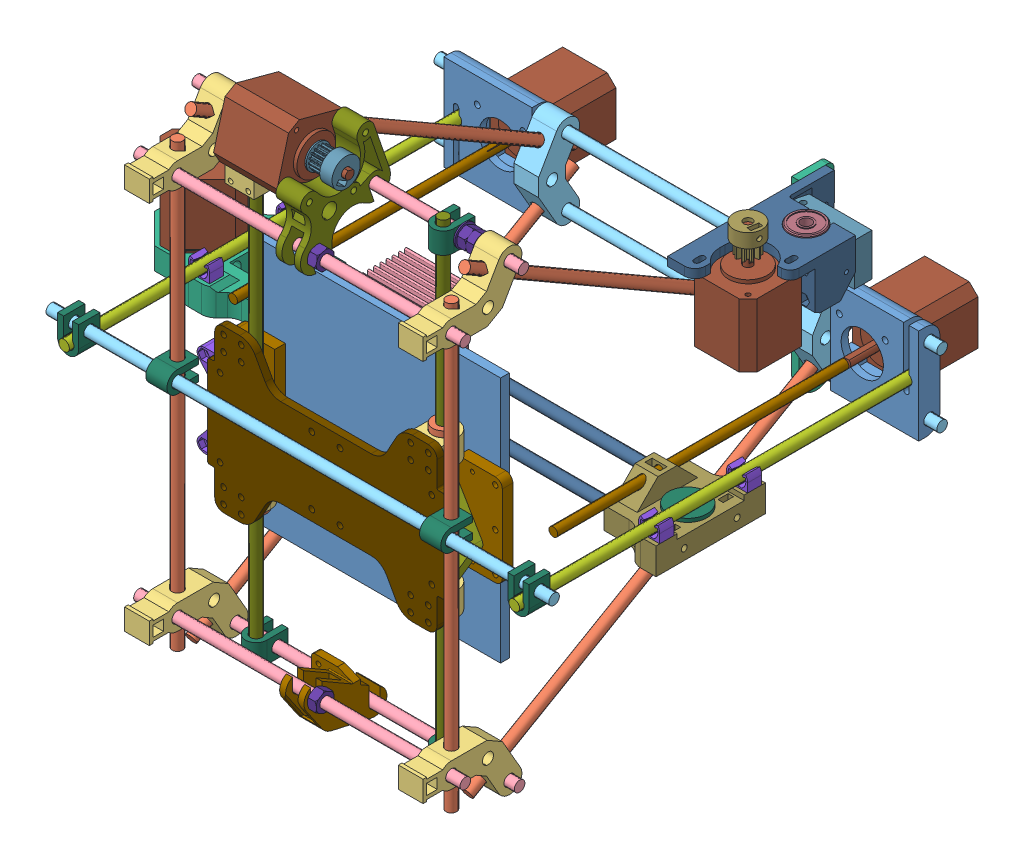
SolidWorks assembly eMAKER huxley, configuration Default. Lengths in mm.
Overall size (320.35 301.66 278.93).
103 component instances, 46 part files, 161 mates.
Components (placement in the parent):
- z-motor-bracket-3: z-motor-bracket [Default] at (-30.685 -17.6925 28.2121) size (50 54.1 12)
- M6x250-1: M6x250 [Default] at (26.315 14.5091 24.1308) x (-0.863161 -0.437281 0.252464) z (0 0.5 0.866025) size (6 6 250)
- frame-vertex-foot-2: frame-vertex-foot [Default] at (19.315 117.86 255.1395) x (0 -1 0) z (1 0 0) size (33.05 56 14)
- frame-vertex-foot-3: frame-vertex-foot [Default] at (33.315 -99.14 255.1395) x (0 1 0) z (-1 0 0) size (33.05 56 14)
- M6x250-3: M6x250 [Default] at (26.315 -120.647 240.3909) x (-0.654172 -0.655015 -0.378173) z (0 0.5 -0.866025) size (6 6 250)
- M6x250-4: M6x250 [Default] at (181.515 5.1965 22.4237) x (-0.767457 -0.555209 -0.32055) z (0 -0.5 0.866025) size (6 6 250)
- M6x250-5: M6x250 [Default] at (181.515 14.5091 24.1308) x (-0.550207 0.723156 -0.417514) z (0 0.5 0.866025) size (6 6 250)
- M6x250-6: M6x250 [Default] at (181.515 127.3875 248.1395) x (0.965547 0 0.260228) z (0 -1 0) size (6 6 250)
- frame-vertex-foot-5: frame-vertex-foot [Default] at (174.515 117.86 255.1395) x (0 -1 0) z (1 0 0) size (33.05 56 14)
- frame-vertex-foot-6: frame-vertex-foot [Default] at (188.515 -99.14 255.1395) x (0 1 0) z (-1 0 0) size (33.05 56 14)
- z-motor-bracket-4: z-motor-bracket [Default] at (238.515 36.4125 28.2121) x (-1 0 0) z (0 0 1) size (50 54.1 12)
- M6x185-19: M6x185 [Default] at (11.4609 136.9125 222.1396) x (0 -0.811297 -0.584634) z (1 0 0) size (6 6 185)
- M6x185-18: M6x185 [Default] at (196.4609 -99.14 255.1395) x (0 -0.62662 0.779325) z (-1 0 0) size (6 6 185)
- M6x285-9: M6x285 [Default] at (245.775 -9.6925 34.2121) x (0 0.518528 0.85506) z (-1 0 0) size (6 6 285)
- M6x285-10: M6x285 [Default] at (245.775 28.4125 34.2121) x (0 0.519725 0.854334) z (-1 0 0) size (6 6 285)
- x-motor-bracket-1: x-motor-bracket [Default] at (-71.685 -10.79 180.1197) x (1 0 0) z (0 1 0) size (79.5 62 24.15)
- z-smooth-rod-11: z-smooth-rod [Default] at (-23.685 9.36 27.4555) x (0.934619 -0.35565 0) z (0 0 1) size (6 6 235)
- 6mm prusa bushing-1: 6mm prusa bushing [Default] at (-23.685 9.36 186.0197) x (1 0 0) z (0 0 -1) size (12 13.42 8)
- M5x165-1: M5x165 [Default] at (1.315 9.36 26.6663) size (5 5 165)
- x-smooth-rod-12: x-smooth-rod [Default] at (226.0938 -4.79 172.1197) x (0 0.339962 0.940439) z (-1 0 0) size (6 6 265)
- x-smooth-rod-13: x-smooth-rod [Default] at (226.0938 -4.79 142.1197) x (0 0.525009 0.851096) z (-1 0 0) size (6 6 265)
- SY35ST26-1: SY35ST26 [Default] at (1.315 9.36 -7.7879) size (35.2 35.2 57)
- SY35ST26-2: SY35ST26 [Default] at (-49.685 37.61 157.1197) x (0.707107 0 -0.707107) z (0 -1 0) size (35.2 35.2 57)
- x-idler-bracket-1: x-idler-bracket [Default] at (259.515 -10.79 134.1197) x (-1 0 0) z (0 1 0) size (37.5 62 24.15)
- 6mm prusa bushing-2: 6mm prusa bushing [Default] at (-23.685 9.36 136.2197) x (1 0 0) z (0 0 -1) size (12 13.42 8)
- 6mm prusa bushing-3: 6mm prusa bushing [Default] at (231.515 9.36 136.2197) x (1 0 0) z (0 0 -1) size (12 13.42 8)
- 6mm prusa bushing-4: 6mm prusa bushing [Default] at (231.515 9.36 186.0197) x (1 0 0) z (0 0 -1) size (12 13.42 8)
- z-smooth-rod-14: z-smooth-rod [Default] at (231.515 9.36 27.4555) x (0.911514 -0.411268 0) z (0 0 1) size (6 6 235)
- M5x165-2: M5x165 [Default] at (206.515 9.36 50.3085) x (0.668515 -0.743699 0) z (0 0 1) size (5 5 165)
- SY35ST26-3: SY35ST26 [Default] at (206.515 9.36 -7.7879) size (35.2 35.2 57)
- x-carriage-1: x-carriage [Default] at (38.366 -13.79 170.1197) x (1 0 0) z (0 1 0) size (40 48 15.15)
- T2_5x16-drive-pulley 00-3: T2_5x16-drive-pulley 00 [Pulley-16-T2,5-16-2-Mekanex] at (-49.685 -1.7881 157.1197) x (0 -1 0) z (-0.972248 0 -0.233951) size (16.4 16 16)
- idler-cover-1: idler-cover [Default] at (224.515 3.61 157.1197) x (0.998064 0 -0.062193) z (0 -1 0) size (21.8 21.8 6.5)
- M6x185-20: M6x185 [Default] at (11.4609 117.86 255.1395) x (0 -0.811297 -0.584634) z (1 0 0) size (6 6 185)
- y-motor-bracket-1: y-motor-bracket [Default] at (98.0023 154.9125 243.1396) x (0 -1 0) z (1 0 0) size (60.24 51 14)
- SY35ST26-4: SY35ST26 [Default] at (62.0023 154.9125 243.1396) x (0 -0.258819 -0.965926) z (1 0 0) size (35.2 35.2 57)
- T2_5x16-drive-pulley 00-4: T2_5x16-drive-pulley 00 [Pulley-16-T2,5-16-2-Mekanex] at (100.9004 154.9125 243.1396) x (1 0 0) z (0 -0.512087 -0.858933) size (16.4 16 16)
- NORDEX-DJS-M4-6-1: NORDEX-DJS-M4-6 [DJS-M4-6] at (117.0023 117.86 255.1395) x (0 0.278292 0.960497) z (-1 0 0) size (10 11.1 5)
- nozzle-mounting-1: nozzle-mounting [Default] at (58.366 1.36 161.0197) x (1 0 0) z (0 1 0) size (40 28.8 11)
- extruder-nozzle-assy 00-1: extruder-nozzle-assy 00 [Default] at (63.5779 17.5931 168.6891) x (-1 0 0) z (0 0 1) size (38 22.2 54)
  - heater-block-1: heater-block [Default] at (-5.288 -2.2669 4.3305) size (15 15 8)
  - heatsink-block-1: heatsink-block [Default] at (24.212 12.2331 0.3305) x (-1 0 0) z (0 -1 0) size (38 8 8)
  - barrel-1: barrel [Default] at (5.212 8.2331 8.3305) x (0.956054 0.29319 0) z (0 0 -1) size (5 5 13)
  - heatsink-1: heatsink [Default] at (24.212 4.2331 -18.6695) x (0 0 -1) z (-1 0 0) size (38 10.2 38)
  - heat-shield-1: heat-shield [Default] at (5.212 12.7331 12.3305) x (1 0 0) z (0 1 0) size (38 20 3)
  - heat-spacer-1: heat-spacer [Default] at (5.212 4.2331 -7.6695) x (-1 0 0) z (0 0 -1) size (38 8 3)
  - nozzle-1: nozzle [Default] at (5.212 8.2331 16.3305) x (-0.923728 -0.383049 0) z (0 0 -1) size (5 5 8)
  - nozzle-shield-1: nozzle-shield [Default] at (5.212 8.2331 12.3305) size (16 16 3.5)
- M6x250-16: M6x250 [Default] at (26.315 129.077 248.1395) x (0.996264 0 0.086361) z (0 -1 0) size (6 6 250)
- M6x185-17: M6x185 [Default] at (194.233 -118.1925 222.1396) x (0 0.636552 -0.771234) z (-1 0 0) size (6 6 185)
- y-idler-bracket-1: y-idler-bracket [Default] at (98.0023 -332.3009 222.1722) x (1 0 0) z (0 0.000042 1) size (23.8 32.28 47)
- NORDEX-DJS-M4-6-2: NORDEX-DJS-M4-6 [DJS-M4-6] at (117.0023 -99.14 255.1395) x (0 -0.039629 0.999214) z (-1 0 0) size (10 11.1 5)
- extruder-drive 00-1: extruder-drive 00 [Default] at (193.707 73.5909 70.6403) x (0 0 -1) z (0 -1 0) size (89.5 61.93 59)
  - M6-Block-1: M6-Block [Default] at (7.0532 4.408 -6.7166) size (89.5 43 28)
  - SY35ST26-1: SY35ST26 [Default] at (-25.9468 4.408 34.2834) x (-1 0 0) z (0 0 -1) size (35.2 35.2 57)
  - 6mm hob-1: 6mm hob [Default] at (7.0532 4.408 -0.7269) x (0.604093 -0.796913 0) z (0 0 1) size (8 8 15)
  - Spur Gear MOD 1 60 tooth-1: Spur Gear MOD 1 60 tooth [Spur-Gear-10060-M08-Mekanex] at (7.0532 4.408 -8.7166) size (61.93 61.93 16) (hidden)
  - Spur-Gear-10010-M08-Mekanex 5mm bore-1: Spur-Gear-10010-M08-Mekanex 5mm bore [Spur-Gear-10010-M08-Mekanex] at (-25.9468 4.408 -8.7166) x (0.986376 0.164509 0) z (0 0 1) size (16 16 16)
  - 624-bearing-1: 624-bearing [Default] at (7.0532 4.408 20.7834) x (-0.515821 0.856696 0) z (0 0 1) size (19 19 6)
  - 624-bearing-2: 624-bearing [Default] at (7.0532 4.408 -3.2166) x (-0.515821 0.856696 0) z (0 0 1) size (19 19 6)
  - idler-bracket-1: idler-bracket [Default] at (20.3032 4.408 -3.1666) x (0 1 0) z (0 0 1) size (37 10 24)
  - 624-bearing-3: 624-bearing [Default] at (20.3032 4.408 10.3334) x (-0.515821 0.856696 0) z (0 0 1) size (19 19 6)
- y-bar-clamp-1: y-bar-clamp [Default] at (50.915 142.9125 228.1396) x (0 0 -1) z (0 -1 0) size (18 12 12)
- y-bar-clamp-2: y-bar-clamp [Default] at (156.915 142.9125 228.1396) x (0 0 -1) z (0 -1 0) size (18 12 12)
- y-bar-clamp-3: y-bar-clamp [Default] at (50.915 -112.1925 228.1396) x (0 0 -1) z (0 -1 0) size (18 12 12)
- y-bar-clamp-4: y-bar-clamp [Default] at (156.915 -112.1925 228.1396) x (0 0 -1) z (0 -1 0) size (18 12 12)
- y-bar-clamp-5: y-bar-clamp [Default] at (231.515 9.36 248.1395) x (0 1 0) z (0 0 1) size (18 12 12)
- y-bar-clamp-6: y-bar-clamp [Default] at (187.515 15.36 254.1395) x (0 0 -1) z (-1 0 0) size (18 12 12)
- y-bar-clamp-7: y-bar-clamp [Default] at (32.315 15.36 254.1395) x (0 0 -1) z (-1 0 0) size (18 12 12)
- y-bar-clamp-8: y-bar-clamp [Default] at (-23.685 9.36 248.1395) x (0 1 0) z (0 0 1) size (18 12 12)
- y-smooth-rod-18: y-smooth-rod [Default] at (156.915 146.1076 228.1396) x (-0.289261 0 0.95725) z (0 -1 0) size (6 6 270)
- y-smooth-rod-19: y-smooth-rod [Default] at (50.915 146.1076 228.1396) x (-0.633039 0 -0.77412) z (0 -1 0) size (6 6 270)
- M6-washer-thin-1: M6-washer-thin [Default] at (34.115 136.9125 222.1396) x (0 0 1) z (-1 0 0) size (12.3 12.3 0.8)
- M6-washer-thin-2: M6-washer-thin [Default] at (44.915 136.9125 222.1396) x (0 0 1) z (-1 0 0) size (12.3 12.3 0.8)
- M6-washer-thin-3: M6-washer-thin [Default] at (163.715 136.9125 222.1396) x (0 0 1) z (-1 0 0) size (12.3 12.3 0.8)
- M6-washer-thin-4: M6-washer-thin [Default] at (174.515 136.9125 222.1396) x (0 0 1) z (-1 0 0) size (12.3 12.3 0.8)
- NORDEX-DJS-M4-6-3: NORDEX-DJS-M4-6 [DJS-M4-6] at (39.115 136.9125 222.1396) x (0 -0.039629 0.999214) z (-1 0 0) size (10 11.1 5)
- NORDEX-DJS-M4-6-4: NORDEX-DJS-M4-6 [DJS-M4-6] at (44.115 136.9125 222.1396) x (0 -0.039629 0.999214) z (-1 0 0) size (10 11.1 5)
- NORDEX-DJS-M4-6-5: NORDEX-DJS-M4-6 [DJS-M4-6] at (173.715 136.9125 222.1396) x (0 -0.039629 0.999214) z (-1 0 0) size (10 11.1 5)
- NORDEX-DJS-M4-6-6: NORDEX-DJS-M4-6 [DJS-M4-6] at (168.715 136.9125 222.1396) x (0 -0.039629 0.999214) z (-1 0 0) size (10 11.1 5)
- frog-1: frog [Default] at (166.8514 -49.8233 237.6396) x (0 1 0) z (0 0 1) size (91.6 134 4)
- NORDEX-DJS-M4-6-7: NORDEX-DJS-M4-6 [DJS-M4-6] at (98.2023 -118.1925 222.1396) x (0 -0.039629 0.999214) z (-1 0 0) size (10 11.1 5)
- NORDEX-DJS-M4-6-8: NORDEX-DJS-M4-6 [DJS-M4-6] at (98.0023 136.9125 222.1396) x (0 -0.708811 0.705398) z (-1 0 0) size (10 11.1 5)
- bed-plate-1: bed-plate [Default] at (173.915 67.284 207.6396) x (-1 0 0) z (0 0 1) size (140 140 5)
- LM6UU-1: LM6UU [Default] at (48.866 -4.79 142.1197) x (0 0.332887 -0.942967) z (1 0 0) size (12 12 19)
- LM6UU-2: LM6UU [Default] at (48.866 -4.79 172.1197) x (0 0.332887 -0.942967) z (1 0 0) size (12 12 19)
- bearing-holder-1: bearing-holder [Default] at (156.915 28.0345 228.1396) x (0 0 -1) z (0 1 0) size (17.75 16.5 13.5)
- LM6UU-3: LM6UU [Default] at (156.915 25.8345 228.1396) x (-0.937496 0 -0.347997) z (0 1 0) size (12 12 19)
- bearing-holder-2: bearing-holder [Default] at (50.915 109.8872 228.1396) x (0 0 -1) z (0 1 0) size (17.75 16.5 13.5)
- LM6UU-4: LM6UU [Default] at (50.915 107.6872 228.1396) x (-0.12842 0 -0.99172) z (0 1 0) size (12 12 19)
- bearing-holder-3: bearing-holder [Default] at (156.915 -33.2655 228.1396) x (0 0 -1) z (0 -1 0) size (17.75 16.5 13.5)
- LM6UU-5: LM6UU [Default] at (156.915 -48.9655 228.1396) x (-0.937496 0 -0.347997) z (0 1 0) size (12 12 19)
- y-belt-clip-1: y-belt-clip [Default] at (100.315 2.6554 240.1396) x (0 -1 0) z (1 0 0) size (13.5 5 7)
- frame-vertex-1: frame-vertex [Default] at (188.515 -9.6925 34.2121) x (0 -0.5 0.866025) z (-1 0 0) size (33.05 47 14)
- frame-vertex-2: frame-vertex [Default] at (33.315 -9.6925 34.2121) x (0 -0.5 0.866025) z (-1 0 0) size (33.05 47 14)
- extruder-drive-holder-1: extruder-drive-holder [Default] at (174.515 1.0025 31.2121) x (0 1 0) z (-1 0 0) size (108 20 4)
- bearing-holder-4: bearing-holder [Default] at (50.915 -33.2655 228.1396) x (0 0 -1) z (0 -1 0) size (17.75 16.5 13.5)
- LM6UU-6: LM6UU [Default] at (50.915 -31.0655 228.1396) x (-0.649924 0 0.759999) z (0 -1 0) size (12 12 19)
- spring-anchor-double-1: spring-anchor-double [Default] at (159.915 23.3853 229.6396) x (0 -1 0) z (0 0 1) size (52 21 8)
- spring-anchor-single-1: spring-anchor-single [Default] at (47.915 -28.6147 229.6396) x (0 1 0) z (0 0 1) size (52 21 8)
- M6x285-11: M6x285 [Default] at (245.775 15.36 254.1395) x (0 0.518528 0.85506) z (-1 0 0) size (6 6 285)
- bed-mounting-plate-1: bed-mounting-plate [Default] at (155.915 23.284 212.6396) x (0 -1 0) z (0 0 1) size (52 25 6)
- bed-mounting-plate-2: bed-mounting-plate [Default] at (51.915 -28.716 212.6396) x (0 1 0) z (0 0 1) size (52 25 6)
Mates (geometry in assembly coordinates):
- Coincident8: coincident aligned: plane of M6x250-1 through (26.315 14.5091 24.1308) normal (0 -0.5 -0.866025); plane of M6x250-5 through (181.515 14.5091 24.1308) normal (0 -0.5 -0.866025)
- Coincident12: coincident aligned: plane of M6x185-19 through (11.4609 136.9125 222.1396) normal (-1 0 0); plane of M6x185-18 through (11.4609 -99.14 255.1395) normal (-1 0 0)
- Coincident13: coincident aligned: plane of M6x285-9 through (245.775 -9.6925 34.2121) normal (1 0 0); plane of M6x285-10 through (245.775 28.4125 34.2121) normal (1 0 0)
- Concentric22: concentric aligned: cylinder of z-motor-bracket-3 through (-23.685 9.36 40.2121) axis (0 0 -1) radius 3.15; cylinder of z-smooth-rod-11 through (-23.685 9.36 262.4555) axis (0 0 -1) radius 3
- Concentric25: concentric aligned: cylinder of z-motor-bracket-3 through (1.315 9.36 40.2121) axis (0 0 -1) radius 12; cylinder of M5x165-1 through (1.315 9.36 191.6663) axis (0 0 -1) radius 2.5
- Concentric26: concentric aligned: cylinder of x-motor-bracket-1 through (-37.185 -4.79 172.1197) axis (1 0 0) radius 3.15; cylinder of x-smooth-rod-12 through (-38.9062 -4.79 172.1197) axis (1 0 0) radius 3
- Concentric27: concentric aligned: cylinder of x-motor-bracket-1 through (-37.185 -4.79 142.1197) axis (1 0 0) radius 3.15; cylinder of x-smooth-rod-13 through (-38.9062 -4.79 142.1197) axis (1 0 0) radius 3
- Coincident16: coincident aligned: plane of x-smooth-rod-12 through (226.0938 -4.79 172.1197) normal (1 0 0); plane of x-smooth-rod-13 through (226.0938 -4.79 142.1197) normal (1 0 0)
- Concentric28: concentric anti-aligned: cylinder of z-motor-bracket-3 through (-11.685 -3.64 40.2121) axis (0 0 -1) radius 1.7; cylinder of SY35ST26-1 through (-11.685 -3.64 28.2121) axis (0 0 1) radius 1.25
- Concentric29: concentric anti-aligned: cylinder of z-motor-bracket-3 through (14.315 22.36 40.2121) axis (0 0 -1) radius 1.7; cylinder of SY35ST26-1 through (14.315 22.36 28.2121) axis (0 0 1) radius 1.25
- Coincident17: coincident anti-aligned: plane of z-motor-bracket-3 through (-30.685 36.4125 28.2121) normal (0 0 -1); plane of SY35ST26-1 through (-16.285 26.96 28.2121) normal (0 0 1)
- Concentric30: concentric anti-aligned: cylinder of x-motor-bracket-1 through (-49.685 -10.79 175.5044) axis (0 1 0) radius 1.75; cylinder of SY35ST26-2 through (-49.685 1.61 175.5044) axis (0 -1 0) radius 1.25
- Concentric31: concentric anti-aligned: cylinder of x-motor-bracket-1 through (-49.685 -10.79 138.7349) axis (0 1 0) radius 1.75; cylinder of SY35ST26-2 through (-49.685 1.61 138.7349) axis (0 -1 0) radius 1.25
- Coincident18: coincident anti-aligned: plane of x-motor-bracket-1 through (-30.685 1.61 134.1197) normal (0 1 0); plane of SY35ST26-2 through (-49.685 1.61 182.0098) normal (0 -1 0)
- Concentric34: concentric anti-aligned: cylinder of x-smooth-rod-13 through (-38.9062 -4.79 142.1197) axis (1 0 0) radius 3; cylinder of x-idler-bracket-1 through (246.4245 -4.79 142.1197) axis (-1 0 0) radius 3.15
- Concentric35: concentric anti-aligned: cylinder of x-smooth-rod-12 through (-38.9062 -4.79 172.1197) axis (1 0 0) radius 3; cylinder of x-idler-bracket-1 through (246.4245 -4.79 172.1197) axis (-1 0 0) radius 3.15
- Concentric39: concentric aligned: cylinder of z-motor-bracket-4 through (231.515 9.36 40.2121) axis (0 0 -1) radius 3.15; cylinder of z-smooth-rod-14 through (231.515 9.36 262.4555) axis (0 0 -1) radius 3
- Coincident23: coincident aligned: plane of z-smooth-rod-11 through (-23.685 9.36 27.4555) normal (0 0 -1); plane of z-smooth-rod-14 through (231.515 9.36 27.4555) normal (0 0 -1)
- Concentric42: concentric anti-aligned: cylinder of z-motor-bracket-4 through (193.515 -3.64 40.2121) axis (0 0 -1) radius 1.7; cylinder of SY35ST26-3 through (193.515 -3.64 28.2121) axis (0 0 1) radius 1.25
- Concentric43: concentric anti-aligned: cylinder of z-motor-bracket-4 through (219.515 22.36 40.2121) axis (0 0 -1) radius 1.7; cylinder of SY35ST26-3 through (219.515 22.36 28.2121) axis (0 0 1) radius 1.25
- Coincident26: coincident anti-aligned: plane of z-motor-bracket-4 through (238.515 -17.6925 28.2121) normal (0 0 -1); plane of SY35ST26-3 through (188.915 26.96 28.2121) normal (0 0 1)
- Concentric51: concentric aligned: cylinder of SY35ST26-2 through (-49.685 -19.39 157.1197) axis (0 1 0) radius 2.5; cylinder of T2_5x16-drive-pulley 00-3 through (-49.685 -1.7881 157.1197) axis (0 1 0) radius 2.65
- Distance6: distance = 1 mm anti-aligned: plane of T2_5x16-drive-pulley 00-3 through (-50.2798 -1.39 159.5914) normal (0 1 0); plane of SY35ST26-2 through (-49.685 -0.39 157.1197) normal (0 -1 0)
- Concentric53: concentric aligned: cylinder of x-idler-bracket-1 through (224.515 -10.79 157.1197) axis (0 1 0) radius 1.65; cylinder of idler-cover-1 through (224.515 -2.89 157.1197) axis (0 1 0) radius 1.65
- Coincident36: coincident anti-aligned: plane of x-idler-bracket-1 through (200.015 1.61 180.1197) normal (0 1 0); plane of idler-cover-1 through (224.515 1.61 157.1197) normal (0 -1 0)
- Coincident38: coincident aligned: plane of M6x185-19 through (196.4609 136.9125 222.1396) normal (1 0 0); plane of M6x185-20 through (196.4609 117.86 255.1395) normal (1 0 0)
- Concentric65: concentric aligned: cylinder of M6x185-19 through (196.4609 136.9125 222.1396) axis (-1 0 0) radius 3; cylinder of y-motor-bracket-1 through (112.0023 136.9125 222.1396) axis (-1 0 0) radius 3.15
- Concentric69: concentric aligned: cylinder of y-motor-bracket-1 through (112.0023 154.9125 243.1396) axis (-1 0 0) radius 13; cylinder of SY35ST26-4 through (100.0023 154.9125 243.1396) axis (-1 0 0) radius 11
- Concentric70: concentric anti-aligned: cylinder of y-motor-bracket-1 through (112.0023 138.9908 233.9472) axis (-1 0 0) radius 1.65; cylinder of SY35ST26-4 through (98.0023 138.9908 233.9472) axis (1 0 0) radius 1.25
- Coincident39: coincident anti-aligned: plane of y-motor-bracket-1 through (98.0023 132.7028 269.9952) normal (-1 0 0); plane of SY35ST26-4 through (98.0023 176.468 255.5847) normal (1 0 0)
- Concentric71: concentric aligned: cylinder of SY35ST26-4 through (119.0023 154.9125 243.1396) axis (-1 0 0) radius 2.5; cylinder of T2_5x16-drive-pulley 00-4 through (100.9004 154.9125 243.1396) axis (-1 0 0) radius 2.65
- Concentric72: concentric anti-aligned: cylinder of M6x185-20 through (196.4609 117.86 255.1395) axis (-1 0 0) radius 3; cylinder of NORDEX-DJS-M4-6-1 through (112.0023 117.86 255.1395) axis (1 0 0) radius 3
- Coincident41: coincident anti-aligned: plane of y-motor-bracket-1 through (112.0023 132.7028 269.9952) normal (1 0 0); plane of NORDEX-DJS-M4-6-1 through (112.0023 119.1339 249.5648) normal (-1 0 0)
- Concentric77: concentric aligned: cylinder of nozzle-mounting-1 through (70.866 1.36 158.1197) axis (0 1 0) radius 1.65; cylinder of x-carriage-1 through (70.866 -13.79 158.1197) axis (0 1 0) radius 1.35
- Concentric78: concentric aligned: cylinder of x-carriage-1 through (45.866 -13.79 158.1197) axis (0 1 0) radius 1.35; cylinder of nozzle-mounting-1 through (45.866 1.36 158.1197) axis (0 1 0) radius 1.65
- Coincident43: coincident anti-aligned: plane of x-carriage-1 through (38.366 1.36 161.1197) normal (0 1 0); plane of nozzle-mounting-1 through (38.366 1.36 132.2197) normal (0 -1 0)
- Distance10: distance = 3 mm anti-aligned: plane of extruder-nozzle-assy 00-1/heatsink-block-1 through (39.366 13.36 161.0197) normal (0 0 -1); plane of nozzle-mounting-1 through (38.366 4.36 158.0197) normal (0 0 1)
- Concentric81: concentric aligned: cylinder of nozzle-mounting-1 through (65.866 9.36 161.0197) axis (0 0 -1) radius 1.65; cylinder of extruder-nozzle-assy 00-1/heatsink-block-1 through (65.866 9.36 161.0197) axis (0 0 -1) radius 1.25
- Concentric82: concentric aligned: cylinder of nozzle-mounting-1 through (50.866 9.36 161.0197) axis (0 0 -1) radius 1.65; cylinder of extruder-nozzle-assy 00-1/heatsink-block-1 through (50.866 9.36 161.0197) axis (0 0 -1) radius 1.25
- Concentric86: concentric anti-aligned: cylinder of M6x250-1 through (26.315 139.5091 240.6371) axis (0 -0.5 -0.866025) radius 3; cylinder of frame-vertex-foot-2 through (26.315 121.306 209.1085) axis (0 0.5 0.866025) radius 3.2
- Concentric88: concentric anti-aligned: cylinder of M6x250-4 through (181.515 -119.8035 238.93) axis (0 0.5 -0.866025) radius 3; cylinder of frame-vertex-foot-6 through (181.515 -102.5861 209.1085) axis (0 -0.5 0.866025) radius 3.2
- Concentric89: concentric aligned: cylinder of frame-vertex-foot-5 through (174.515 136.9125 222.1396) axis (-1 0 0) radius 3.2; cylinder of M6x185-19 through (196.4609 136.9125 222.1396) axis (-1 0 0) radius 3
- Concentric90: concentric aligned: cylinder of frame-vertex-foot-5 through (174.515 117.86 255.1395) axis (-1 0 0) radius 3.2; cylinder of M6x185-20 through (196.4609 117.86 255.1395) axis (-1 0 0) radius 3
- Concentric91: concentric anti-aligned: cylinder of M6x250-5 through (181.515 139.5091 240.6371) axis (0 -0.5 -0.866025) radius 3; cylinder of frame-vertex-foot-5 through (181.515 121.306 209.1085) axis (0 0.5 0.866025) radius 3.2
- Concentric92: concentric aligned: cylinder of frame-vertex-foot-2 through (19.315 136.9125 222.1396) axis (-1 0 0) radius 3.2; cylinder of M6x185-19 through (196.4609 136.9125 222.1396) axis (-1 0 0) radius 3
- Concentric93: concentric aligned: cylinder of M6x250-6 through (181.515 -122.6125 248.1395) axis (0 1 0) radius 3; cylinder of frame-vertex-foot-5 through (181.515 110.86 248.1395) axis (0 1 0) radius 3.2
- Concentric94: concentric anti-aligned: cylinder of M6x250-6 through (181.515 -122.6125 248.1395) axis (0 1 0) radius 3; cylinder of frame-vertex-foot-6 through (181.515 -92.14 248.1395) axis (0 -1 0) radius 3.2
- Concentric95: concentric aligned: cylinder of frame-vertex-foot-2 through (26.315 110.86 248.1395) axis (0 1 0) radius 3.2; cylinder of M6x250-16 through (26.315 -120.923 248.1395) axis (0 1 0) radius 3
- Concentric96: concentric anti-aligned: cylinder of frame-vertex-foot-3 through (26.315 -92.14 248.1395) axis (0 -1 0) radius 3.2; cylinder of M6x250-16 through (26.315 -120.923 248.1395) axis (0 1 0) radius 3
- Concentric97: concentric aligned: cylinder of frame-vertex-foot-3 through (33.315 -99.14 255.1395) axis (1 0 0) radius 3.2; cylinder of M6x185-18 through (11.4609 -99.14 255.1395) axis (1 0 0) radius 3
- Concentric98: concentric aligned: cylinder of frame-vertex-foot-6 through (188.515 -99.14 255.1395) axis (1 0 0) radius 3.2; cylinder of M6x185-18 through (11.4609 -99.14 255.1395) axis (1 0 0) radius 3
- Concentric102: concentric aligned: cylinder of frame-vertex-foot-3 through (26.315 -102.5861 209.1085) axis (0 -0.5 0.866025) radius 3.2; cylinder of M6x250-3 through (26.315 4.353 23.8845) axis (0 -0.5 0.866025) radius 3
- Concentric103: concentric aligned: cylinder of frame-vertex-foot-3 through (33.315 -118.1925 222.1396) axis (1 0 0) radius 3.2; cylinder of M6x185-17 through (9.233 -118.1925 222.1396) axis (1 0 0) radius 3
- Concentric107: concentric aligned: cylinder of z-motor-bracket-4 through (206.515 9.36 40.2121) axis (0 0 -1) radius 12; cylinder of M5x165-2 through (206.515 9.36 215.3085) axis (0 0 -1) radius 2.5
- Concentric108: concentric anti-aligned: cylinder of z-smooth-rod-11 through (-23.685 9.36 262.4555) axis (0 0 -1) radius 3; cylinder of 6mm prusa bushing-2 through (-23.685 9.36 128.2197) axis (0 0 1) radius 5
- Concentric109: concentric anti-aligned: cylinder of 6mm prusa bushing-3 through (231.515 9.36 128.2197) axis (0 0 1) radius 5; cylinder of z-smooth-rod-14 through (231.515 9.36 262.4555) axis (0 0 -1) radius 3
- Concentric112: concentric anti-aligned: cylinder of x-idler-bracket-1 through (206.515 9.36 126.1197) axis (0 0 1) radius 2.7; cylinder of M5x165-2 through (206.515 9.36 215.3085) axis (0 0 -1) radius 2.5
- Concentric114: concentric aligned: cylinder of M6x185-18 through (11.4609 -99.14 255.1395) axis (1 0 0) radius 3; cylinder of y-idler-bracket-1 through (98.2023 -99.14 255.1395) axis (1 0 0) radius 3.2
- Concentric115: concentric aligned: cylinder of M6x185-17 through (9.233 -118.1925 222.1396) axis (1 0 0) radius 3; cylinder of y-idler-bracket-1 through (98.2023 -118.1926 222.1395) axis (1 0 0) radius 3.2
- Coincident52: coincident aligned: plane of y-motor-bracket-1 through (112.0023 132.7028 269.9952) normal (1 0 0); plane of y-idler-bracket-1 through (112.0023 -99.14 255.1395) normal (1 0 0)
- Coincident53: coincident anti-aligned: plane of y-idler-bracket-1 through (112.0023 -99.14 255.1395) normal (1 0 0); plane of NORDEX-DJS-M4-6-2 through (112.0023 -96.1691 250.2534) normal (-1 0 0)
- Concentric116: concentric aligned: cylinder of M6x185-18 through (11.4609 -99.14 255.1395) axis (1 0 0) radius 3; cylinder of NORDEX-DJS-M4-6-2 through (112.0023 -99.14 255.1395) axis (1 0 0) radius 3
- Concentric120: concentric anti-aligned: cylinder of M6x185-19 through (196.4609 136.9125 222.1396) axis (-1 0 0) radius 3; cylinder of y-bar-clamp-1 through (44.915 136.9125 222.1396) axis (1 0 0) radius 3.15
- Concentric121: concentric anti-aligned: cylinder of M6x185-19 through (196.4609 136.9125 222.1396) axis (-1 0 0) radius 3; cylinder of y-bar-clamp-2 through (150.915 136.9125 222.1396) axis (1 0 0) radius 3.15
- Concentric122: concentric aligned: cylinder of M6x185-17 through (9.233 -118.1925 222.1396) axis (1 0 0) radius 3; cylinder of y-bar-clamp-3 through (44.915 -118.1925 222.1396) axis (1 0 0) radius 3.15
- Concentric123: concentric aligned: cylinder of M6x185-17 through (9.233 -118.1925 222.1396) axis (1 0 0) radius 3; cylinder of y-bar-clamp-4 through (150.915 -118.1925 222.1396) axis (1 0 0) radius 3.15
- Concentric124: concentric anti-aligned: cylinder of M6x250-6 through (181.515 -122.6125 248.1395) axis (0 1 0) radius 3; cylinder of y-bar-clamp-6 through (181.515 21.36 248.1395) axis (0 -1 0) radius 3.15
- Concentric125: concentric aligned: cylinder of z-smooth-rod-14 through (231.515 9.36 262.4555) axis (0 0 -1) radius 3; cylinder of y-bar-clamp-5 through (231.515 9.36 260.1395) axis (0 0 -1) radius 3.3
- Concentric126: concentric anti-aligned: cylinder of y-bar-clamp-5 through (237.515 15.36 254.1395) axis (-1 0 0) radius 3.15; cylinder of y-bar-clamp-6 through (175.515 15.36 254.1395) axis (1 0 0) radius 3.3
- Concentric127: concentric anti-aligned: cylinder of M6x250-16 through (26.315 -120.923 248.1395) axis (0 1 0) radius 3; cylinder of y-bar-clamp-7 through (26.315 21.36 248.1395) axis (0 -1 0) radius 3.15
- Concentric128: concentric aligned: cylinder of z-smooth-rod-11 through (-23.685 9.36 262.4555) axis (0 0 -1) radius 3; cylinder of y-bar-clamp-8 through (-23.685 9.36 260.1395) axis (0 0 -1) radius 3.3
- Concentric129: concentric anti-aligned: cylinder of y-bar-clamp-7 through (20.315 15.36 254.1395) axis (1 0 0) radius 3.3; cylinder of y-bar-clamp-8 through (-17.685 15.36 254.1395) axis (-1 0 0) radius 3.15
- Concentric130: concentric aligned: cylinder of y-bar-clamp-2 through (156.915 130.9125 228.1396) axis (0 1 0) radius 3.3; cylinder of y-smooth-rod-18 through (156.915 -123.8924 228.1396) axis (0 1 0) radius 3
- Concentric131: concentric aligned: cylinder of y-bar-clamp-4 through (156.915 -124.1925 228.1396) axis (0 1 0) radius 3.3; cylinder of y-smooth-rod-18 through (156.915 -123.8924 228.1396) axis (0 1 0) radius 3
- Concentric132: concentric aligned: cylinder of y-bar-clamp-1 through (50.915 130.9125 228.1396) axis (0 1 0) radius 3.3; cylinder of y-smooth-rod-19 through (50.915 -123.8924 228.1396) axis (0 1 0) radius 3
- Concentric134: concentric aligned: cylinder of y-bar-clamp-3 through (50.915 -124.1925 228.1396) axis (0 1 0) radius 3.3; cylinder of y-smooth-rod-19 through (50.915 -123.8924 228.1396) axis (0 1 0) radius 3
- Coincident57: coincident aligned: plane of y-smooth-rod-18 through (156.915 146.1076 228.1396) normal (0 1 0); plane of y-smooth-rod-19 through (50.915 146.1076 228.1396) normal (0 1 0)
- Concentric135: concentric anti-aligned: cylinder of M6x185-19 through (196.4609 136.9125 222.1396) axis (-1 0 0) radius 3; cylinder of M6-washer-thin-1 through (33.315 136.9125 222.1396) axis (1 0 0) radius 3.25
- Concentric136: concentric anti-aligned: cylinder of M6x185-19 through (196.4609 136.9125 222.1396) axis (-1 0 0) radius 3; cylinder of NORDEX-DJS-M4-6-3 through (34.115 136.9125 222.1396) axis (1 0 0) radius 3
- Coincident59: coincident aligned: cylinder of M6x185-19 through (196.4609 136.9125 222.1396) axis (-1 0 0) radius 3; circle of NORDEX-DJS-M4-6-4
- Concentric137: concentric anti-aligned: cylinder of M6x185-19 through (196.4609 136.9125 222.1396) axis (-1 0 0) radius 3; cylinder of M6-washer-thin-2 through (44.115 136.9125 222.1396) axis (1 0 0) radius 3.25
- Coincident60: coincident anti-aligned: plane of M6-washer-thin-1 through (34.115 136.9125 222.1396) normal (1 0 0); plane of NORDEX-DJS-M4-6-3 through (34.115 139.8834 217.2535) normal (-1 0 0)
- Coincident61: coincident anti-aligned: plane of NORDEX-DJS-M4-6-3 through (39.115 139.8834 217.2535) normal (1 0 0); plane of NORDEX-DJS-M4-6-4 through (39.115 139.8834 217.2535) normal (-1 0 0)
- Coincident62: coincident anti-aligned: plane of M6-washer-thin-2 through (44.115 136.9125 222.1396) normal (-1 0 0); plane of NORDEX-DJS-M4-6-4 through (44.115 139.8834 217.2535) normal (1 0 0)
- Coincident63: coincident anti-aligned: plane of y-bar-clamp-1 through (44.915 130.9125 228.1396) normal (-1 0 0); plane of M6-washer-thin-2 through (44.915 136.9125 222.1396) normal (1 0 0)
- Concentric138: concentric anti-aligned: cylinder of M6x185-19 through (196.4609 136.9125 222.1396) axis (-1 0 0) radius 3; cylinder of M6-washer-thin-4 through (173.715 136.9125 222.1396) axis (1 0 0) radius 3.25
- Concentric139: concentric anti-aligned: cylinder of M6x185-19 through (196.4609 136.9125 222.1396) axis (-1 0 0) radius 3; cylinder of M6-washer-thin-3 through (162.915 136.9125 222.1396) axis (1 0 0) radius 3.25
- Concentric140: concentric anti-aligned: cylinder of M6x185-19 through (196.4609 136.9125 222.1396) axis (-1 0 0) radius 3; cylinder of NORDEX-DJS-M4-6-5 through (168.715 136.9125 222.1396) axis (1 0 0) radius 3
- Concentric141: concentric anti-aligned: cylinder of M6x185-19 through (196.4609 136.9125 222.1396) axis (-1 0 0) radius 3; cylinder of NORDEX-DJS-M4-6-6 through (163.715 136.9125 222.1396) axis (1 0 0) radius 3
- Coincident64: coincident anti-aligned: plane of frame-vertex-foot-5 through (174.515 117.86 255.1395) normal (-1 0 0); plane of M6-washer-thin-4 through (174.515 136.9125 222.1396) normal (1 0 0)
- Coincident65: coincident anti-aligned: plane of M6-washer-thin-4 through (173.715 136.9125 222.1396) normal (-1 0 0); plane of NORDEX-DJS-M4-6-5 through (173.715 139.8834 217.2535) normal (1 0 0)
- Coincident66: coincident anti-aligned: plane of NORDEX-DJS-M4-6-5 through (168.715 139.8834 217.2535) normal (-1 0 0); plane of NORDEX-DJS-M4-6-6 through (168.715 139.8834 217.2535) normal (1 0 0)
- Coincident67: coincident anti-aligned: plane of M6-washer-thin-3 through (163.715 136.9125 222.1396) normal (1 0 0); plane of NORDEX-DJS-M4-6-6 through (163.715 139.8834 217.2535) normal (-1 0 0)
- Coincident68: coincident anti-aligned: plane of y-bar-clamp-2 through (162.915 130.9125 228.1396) normal (1 0 0); plane of M6-washer-thin-3 through (162.915 136.9125 222.1396) normal (-1 0 0)
- Concentric146: concentric aligned: cylinder of M6x185-20 through (196.4609 117.86 255.1395) axis (-1 0 0) radius 3; cylinder of y-motor-bracket-1 through (112.0023 117.86 255.1395) axis (-1 0 0) radius 3.15
- Concentric148: concentric aligned: cylinder of M6x185-17 through (9.233 -118.1925 222.1396) axis (1 0 0) radius 3; cylinder of NORDEX-DJS-M4-6-7 through (93.2023 -118.1925 222.1396) axis (1 0 0) radius 3
- Coincident95: coincident anti-aligned: plane of y-idler-bracket-1 through (98.2023 -99.14 255.1395) normal (-1 0 0); plane of NORDEX-DJS-M4-6-7 through (98.2023 -115.2216 217.2535) normal (1 0 0)
- Concentric149: concentric anti-aligned: cylinder of M6x185-19 through (196.4609 136.9125 222.1396) axis (-1 0 0) radius 3; cylinder of NORDEX-DJS-M4-6-8 through (93.0023 136.9125 222.1396) axis (1 0 0) radius 3
- Coincident96: coincident: plane of y-motor-bracket-1 through (98.0023 132.7028 269.9952) normal (-1 0 0); line of NORDEX-DJS-M4-6-8 through (98.0023 141.1193 219.2786) axis (0 -0.705398 -0.708811)
- Concentric152: concentric aligned: cylinder of z-motor-bracket-4 through (188.515 28.4125 34.2121) axis (1 0 0) radius 3.15; cylinder of M6x285-10 through (-39.225 28.4125 34.2121) axis (1 0 0) radius 3
- Concentric153: concentric aligned: cylinder of z-motor-bracket-4 through (188.515 -9.6925 34.2121) axis (1 0 0) radius 3.15; cylinder of M6x285-9 through (-39.225 -9.6925 34.2121) axis (1 0 0) radius 3
- Concentric154: concentric anti-aligned: cylinder of z-motor-bracket-3 through (19.315 28.4125 34.2121) axis (-1 0 0) radius 3.15; cylinder of M6x285-10 through (-39.225 28.4125 34.2121) axis (1 0 0) radius 3
- Concentric155: concentric anti-aligned: cylinder of x-smooth-rod-13 through (-38.9062 -4.79 142.1197) axis (1 0 0) radius 3; cylinder of LM6UU-1 through (67.866 -4.79 142.1197) axis (-1 0 0) radius 3
- Concentric156: concentric aligned: cylinder of x-carriage-1 through (68.366 -4.79 142.1197) axis (-1 0 0) radius 6.1; cylinder of LM6UU-1 through (67.866 -4.79 142.1197) axis (-1 0 0) radius 6
- Distance26: distance = 0.5 mm anti-aligned: plane of LM6UU-1 through (67.866 -4.79 142.1197) normal (1 0 0); plane of x-carriage-1 through (68.366 -4.79 142.1197) normal (-1 0 0)
- Concentric157: concentric anti-aligned: cylinder of x-smooth-rod-12 through (-38.9062 -4.79 172.1197) axis (1 0 0) radius 3; cylinder of LM6UU-2 through (67.866 -4.79 172.1197) axis (-1 0 0) radius 3
- Concentric158: concentric aligned: cylinder of x-carriage-1 through (68.366 -4.79 172.1197) axis (-1 0 0) radius 6.1; cylinder of LM6UU-2 through (67.866 -4.79 172.1197) axis (-1 0 0) radius 6
- Distance27: distance = 0.5 mm anti-aligned: plane of x-carriage-1 through (48.366 -4.79 172.1197) normal (1 0 0); plane of LM6UU-2 through (48.866 -4.79 172.1197) normal (-1 0 0)
- Concentric159: concentric anti-aligned: cylinder of frog-1 through (161.915 39.0345 241.6396) axis (0 0 -1) radius 1.6; cylinder of bearing-holder-1 through (161.915 39.0345 237.6396) axis (0 0 1) radius 1.35
- Concentric162: concentric anti-aligned: cylinder of frog-1 through (161.915 30.5345 241.6396) axis (0 0 -1) radius 1.6; cylinder of bearing-holder-1 through (161.915 30.5345 237.6396) axis (0 0 1) radius 1.35
- Coincident100: coincident anti-aligned: plane of frog-1 through (39.915 -29.6163 237.6396) normal (0 0 -1); plane of bearing-holder-1 through (148.665 41.5345 237.6396) normal (0 0 1)
- Concentric163: concentric anti-aligned: cylinder of y-smooth-rod-18 through (156.915 -123.8924 228.1396) axis (0 1 0) radius 3; cylinder of LM6UU-3 through (156.915 44.8345 228.1396) axis (0 -1 0) radius 3
- Concentric164: concentric aligned: cylinder of bearing-holder-1 through (156.915 41.5345 228.1396) axis (0 -1 0) radius 6.2; cylinder of LM6UU-3 through (156.915 44.8345 228.1396) axis (0 -1 0) radius 6
- Coincident101: coincident anti-aligned: plane of bearing-holder-1 through (156.915 41.5345 228.1396) normal (0 1 0); circle of LM6UU-3
- Coincident58: coincident anti-aligned: plane of frame-vertex-foot-2 through (33.315 117.86 255.1395) normal (1 0 0); plane of M6-washer-thin-1 through (33.315 136.9125 222.1396) normal (-1 0 0)
- Coincident102: coincident anti-aligned: plane of frog-1 through (39.915 -29.6163 237.6396) normal (0 0 -1); plane of bearing-holder-2 through (42.665 123.3872 237.6396) normal (0 0 1)
- Concentric167: concentric anti-aligned: cylinder of y-smooth-rod-19 through (50.915 -123.8924 228.1396) axis (0 1 0) radius 3; cylinder of LM6UU-4 through (50.915 126.6872 228.1396) axis (0 -1 0) radius 3
- Coincident103: coincident anti-aligned: plane of bearing-holder-2 through (50.915 123.3872 228.1396) normal (0 1 0); plane of LM6UU-4 through (50.1765 123.3872 222.4372) normal (0 -1 0)
- Concentric169: concentric aligned: cylinder of bearing-holder-2 through (50.915 123.3872 228.1396) axis (0 -1 0) radius 6.2; cylinder of LM6UU-4 through (50.915 126.6872 228.1396) axis (0 -1 0) radius 6
- Distance29: distance = 94 mm anti-aligned: plane of y-bar-clamp-2 through (150.915 130.9125 228.1396) normal (-1 0 0); plane of y-bar-clamp-1 through (56.915 130.9125 228.1396) normal (1 0 0)
- Concentric170: concentric anti-aligned: cylinder of frog-1 through (161.915 -44.2655 241.6396) axis (0 0 -1) radius 1.6; cylinder of bearing-holder-3 through (161.915 -44.2655 237.6396) axis (0 0 1) radius 1.35
- Concentric171: concentric anti-aligned: cylinder of frog-1 through (161.915 -35.7655 241.6396) axis (0 0 -1) radius 1.6; cylinder of bearing-holder-3 through (161.915 -35.7655 237.6396) axis (0 0 1) radius 1.35
- Coincident108: coincident anti-aligned: plane of frog-1 through (39.915 -29.6163 237.6396) normal (0 0 -1); plane of bearing-holder-3 through (165.165 -46.7655 237.6396) normal (0 0 1)
- Concentric172: concentric anti-aligned: cylinder of y-smooth-rod-18 through (156.915 -123.8924 228.1396) axis (0 1 0) radius 3; cylinder of LM6UU-5 through (156.915 -29.9655 228.1396) axis (0 -1 0) radius 3
- Coincident109: coincident anti-aligned: plane of bearing-holder-3 through (156.915 -46.7655 228.1396) normal (0 -1 0); plane of LM6UU-5 through (151.5244 -46.7655 226.1386) normal (0 1 0)
- Distance30: distance = 203 mm anti-aligned: plane of frame-vertex-foot-2 through (19.315 110.86 255.1395) normal (0 -1 0); plane of frame-vertex-foot-3 through (33.315 -92.14 255.1395) normal (0 1 0)
- Distance31: distance = 0.5 mm anti-aligned: plane of T2_5x16-drive-pulley 00-4 through (100.5023 152.7288 244.4415) normal (-1 0 0); plane of SY35ST26-4 through (100.0023 154.9125 243.1396) normal (1 0 0)
- Coincident116: coincident anti-aligned: plane of frog-1 through (39.915 -29.6163 237.6396) normal (0 0 -1); plane of y-belt-clip-1 through (90.8508 -0.2446 237.6396) normal (0 0 1)
- Coincident117: coincident anti-aligned: plane of z-motor-bracket-4 through (188.515 36.4125 40.2121) normal (-1 0 0); plane of frame-vertex-1 through (188.515 -9.6925 34.2121) normal (1 0 0)
- Concentric178: concentric aligned: cylinder of M6x250-5 through (181.515 139.5091 240.6371) axis (0 -0.5 -0.866025) radius 3; cylinder of frame-vertex-1 through (181.515 31.8946 54.2433) axis (0 -0.5 -0.866025) radius 3.2
- Concentric179: concentric aligned: cylinder of M6x285-10 through (-39.225 28.4125 34.2121) axis (1 0 0) radius 3; cylinder of frame-vertex-1 through (188.515 28.4125 34.2121) axis (1 0 0) radius 3.2
- Concentric180: concentric aligned: cylinder of M6x285-9 through (-39.225 -9.6925 34.2121) axis (1 0 0) radius 3; cylinder of frame-vertex-1 through (188.515 -9.6925 34.2121) axis (1 0 0) radius 3.2
- Coincident118: coincident anti-aligned: plane of z-motor-bracket-3 through (19.315 -17.6925 40.2121) normal (1 0 0); plane of frame-vertex-2 through (19.315 -9.6925 34.2121) normal (-1 0 0)
- Concentric181: concentric aligned: cylinder of M6x285-10 through (-39.225 28.4125 34.2121) axis (1 0 0) radius 3; cylinder of frame-vertex-2 through (33.315 28.4125 34.2121) axis (1 0 0) radius 3.2
- Concentric182: concentric aligned: cylinder of M6x285-9 through (-39.225 -9.6925 34.2121) axis (1 0 0) radius 3; cylinder of frame-vertex-2 through (33.315 -9.6925 34.2121) axis (1 0 0) radius 3.2
- Concentric184: concentric anti-aligned: cylinder of M6x250-3 through (26.315 4.353 23.8845) axis (0 -0.5 0.866025) radius 3; cylinder of frame-vertex-2 through (26.315 -7.1303 43.7743) axis (0 0.5 -0.866025) radius 3.2
- Coincident119: coincident anti-aligned: plane of frame-vertex-1 through (174.515 -9.6925 34.2121) normal (-1 0 0); plane of extruder-drive-holder-1 through (174.515 76.8075 27.7121) normal (1 0 0)
- Concentric185: concentric aligned: cylinder of M6x285-10 through (-39.225 28.4125 34.2121) axis (1 0 0) radius 3; cylinder of extruder-drive-holder-1 through (170.515 28.4125 34.2121) axis (1 0 0) radius 3.1
- Concentric187: concentric anti-aligned: cylinder of extruder-drive 00-1/M6-Block-1 through (217.515 65.3075 34.2121) axis (-1 0 0) radius 1.7; cylinder of extruder-drive-holder-1 through (170.515 65.3075 34.2121) axis (1 0 0) radius 2.15
- Concentric197: concentric aligned: cylinder of bearing-holder-4 through (50.915 -46.7655 228.1396) axis (0 1 0) radius 6.2; cylinder of LM6UU-6 through (50.915 -50.0655 228.1396) axis (0 1 0) radius 6
- Coincident121: coincident anti-aligned: plane of bearing-holder-4 through (50.915 -33.2655 228.1396) normal (0 1 0); plane of LM6UU-6 through (47.1779 -33.2655 232.5096) normal (0 -1 0)
- Concentric198: concentric anti-aligned: cylinder of frog-1 through (45.915 -44.2655 241.6396) axis (0 0 -1) radius 1.6; cylinder of bearing-holder-4 through (45.915 -44.2655 237.6396) axis (0 0 1) radius 1.35
- Concentric199: concentric anti-aligned: cylinder of frog-1 through (55.915 -44.2655 241.6396) axis (0 0 -1) radius 1.6; cylinder of bearing-holder-4 through (55.915 -44.2655 237.6396) axis (0 0 1) radius 1.35
- Coincident122: coincident anti-aligned: plane of frog-1 through (39.915 -29.6163 237.6396) normal (0 0 -1); plane of bearing-holder-4 through (59.165 -46.7655 237.6396) normal (0 0 1)
- Concentric200: concentric aligned: cylinder of M6x285-9 through (-39.225 -9.6925 34.2121) axis (1 0 0) radius 3; cylinder of extruder-drive-holder-1 through (170.515 -9.6925 34.2121) axis (1 0 0) radius 3.1
- Coincident123: coincident anti-aligned: plane of extruder-drive 00-1/M6-Block-1 through (174.515 52.3075 118.5871) normal (-1 0 0); plane of extruder-drive-holder-1 through (174.515 76.8075 27.7121) normal (1 0 0)
- Concentric201: concentric anti-aligned: cylinder of y-bar-clamp-8 through (-17.685 15.36 254.1395) axis (-1 0 0) radius 3.15; cylinder of M6x285-11 through (-39.225 15.36 254.1395) axis (1 0 0) radius 3
- Coincident124: coincident aligned: plane of M6x285-10 through (-39.225 28.4125 34.2121) normal (-1 0 0); plane of M6x285-11 through (-39.225 15.36 254.1395) normal (-1 0 0)
- Concentric202: concentric aligned: cylinder of frog-1 through (43.915 19.3853 241.6396) axis (0 0 -1) radius 1.6; cylinder of spring-anchor-single-1 through (43.915 19.3853 237.6396) axis (0 0 -1) radius 1.65
- Parallel1: parallel anti-aligned: plane of frog-1 through (36.915 -27.6163 241.6396) normal (-1 0 0); plane of spring-anchor-single-1 through (47.915 -28.6147 237.6396) normal (1 0 0)
- Coincident126: coincident anti-aligned: plane of frog-1 through (39.915 -29.6163 237.6396) normal (0 0 -1); plane of spring-anchor-single-1 through (30.915 -24.6147 237.6396) normal (0 0 1)
- Concentric204: concentric aligned: cylinder of frog-1 through (163.915 19.3853 241.6396) axis (0 0 -1) radius 1.6; cylinder of spring-anchor-double-1 through (163.915 19.3853 237.6396) axis (0 0 -1) radius 1.65
- Parallel2: parallel anti-aligned: plane of frog-1 through (170.915 -27.6163 241.6396) normal (1 0 0); plane of spring-anchor-double-1 through (159.915 23.3853 237.6396) normal (-1 0 0)
- Coincident128: coincident anti-aligned: plane of frog-1 through (39.915 -29.6163 237.6396) normal (0 0 -1); plane of spring-anchor-double-1 through (163.915 19.3853 237.6396) normal (0 0 1)
- Concentric205: concentric aligned: cylinder of bed-plate-1 through (163.915 19.284 207.6396) axis (0 0 -1) radius 1.5; cylinder of bed-mounting-plate-1 through (163.915 19.284 218.6396) axis (0 0 -1) radius 1.15
- Concentric206: concentric aligned: cylinder of bed-plate-1 through (163.915 -24.716 207.6396) axis (0 0 -1) radius 1.5; cylinder of bed-mounting-plate-1 through (163.915 -24.716 218.6396) axis (0 0 -1) radius 1.15
- Coincident129: coincident anti-aligned: plane of bed-plate-1 through (173.915 -72.716 212.6396) normal (0 0 1); plane of bed-mounting-plate-1 through (176.915 19.284 212.6396) normal (0 0 -1)
- Concentric207: concentric aligned: cylinder of bed-plate-1 through (43.915 -24.716 207.6396) axis (0 0 -1) radius 1.5; cylinder of bed-mounting-plate-2 through (43.915 -24.716 218.6396) axis (0 0 -1) radius 1.15
- Concentric208: concentric aligned: cylinder of bed-plate-1 through (43.915 19.284 207.6396) axis (0 0 -1) radius 1.5; cylinder of bed-mounting-plate-2 through (43.915 19.284 218.6396) axis (0 0 -1) radius 1.15
- Coincident130: coincident anti-aligned: plane of bed-plate-1 through (173.915 -72.716 212.6396) normal (0 0 1); plane of bed-mounting-plate-2 through (30.915 -24.716 212.6396) normal (0 0 -1)
- Parallel3: parallel aligned: plane of extruder-drive 00-1/M6-Block-1 through (198.115 80.3075 99.5871) normal (0 1 0); plane of extruder-drive-holder-1 through (170.515 80.3075 44.2121) normal (0 1 0)
